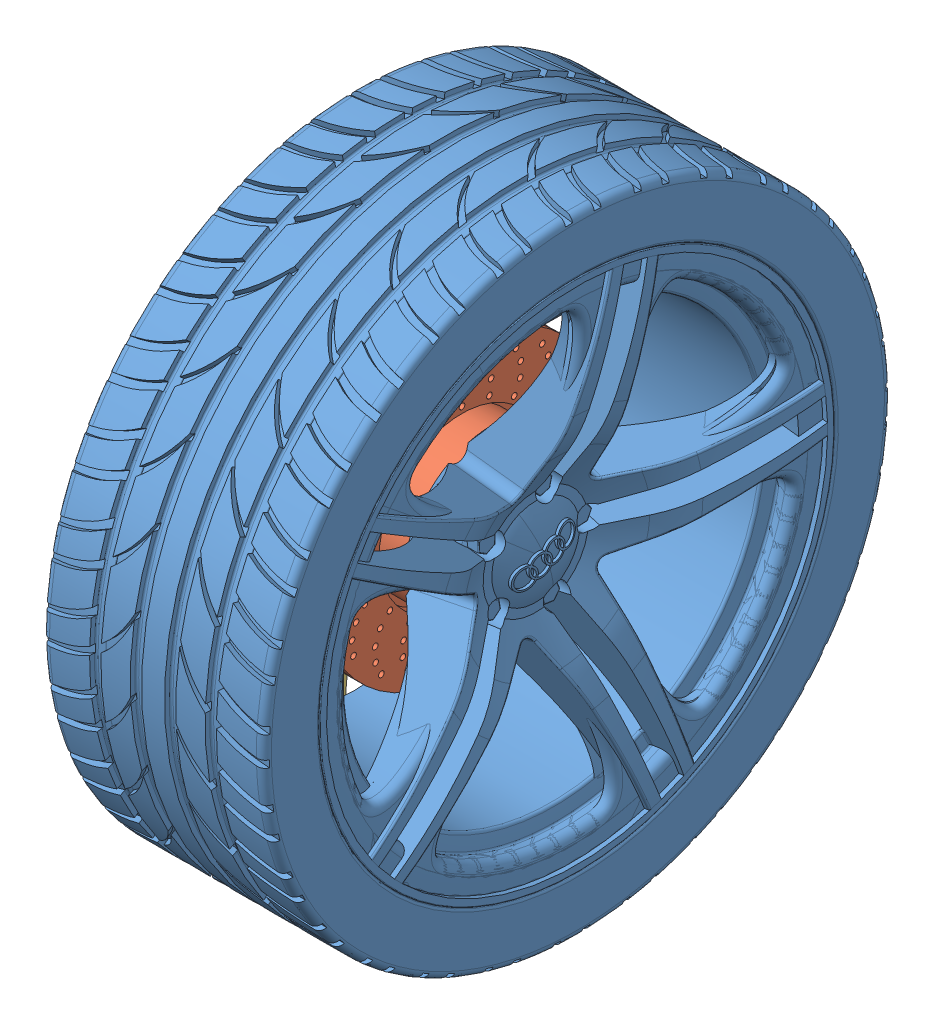
SolidWorks assembly Assem2, configuration Default. Lengths in mm.
Overall size (361.62 873.66 873.66).
3 component instances, 3 part files, 5 mates.
Components (placement in the parent):
- BÁNH XE-1: BÁNH XE [Varsayılan] at (-713.4994 0 0) x (0 0.381849 -0.924225) z (0 -0.924225 -0.381849) size (668.92 273.92 668.92)
- ĐĨA THẮNG-1: ĐĨA THẮNG [Default] at (96.4435 0 0) x (0 0.381849 -0.924225) z (0 -0.924225 -0.381849) size (303 56.33 303)
- KHUNG TREO R-1: KHUNG TREO R [Default] at origin size (231.48 449.46 221.1)
Mates (geometry in assembly coordinates):
- Coincident1: coordinate: point of KHUNG TREO R-1
- Concentric1: concentric aligned: circle of BÁNH XE-1; circle of ĐĨA THẮNG-1
- Coincident2: coincident anti-aligned: plane of BÁNH XE-1 through (284.0476 -12.4245 2.4003) normal (-1 0 0); plane of ĐĨA THẮNG-1 through (656.3936 -13.3647 32.3479) normal (1 0 0)
- Concentric2: concentric aligned: circle of ĐĨA THẮNG-1; circle of KHUNG TREO R-1
- Coincident3: coincident anti-aligned: plane of BÁNH XE-1 through (140.2735 0 0) normal (-1 0 0); plane of KHUNG TREO R-1 through (140.2735 0 0) normal (1 0 0)
